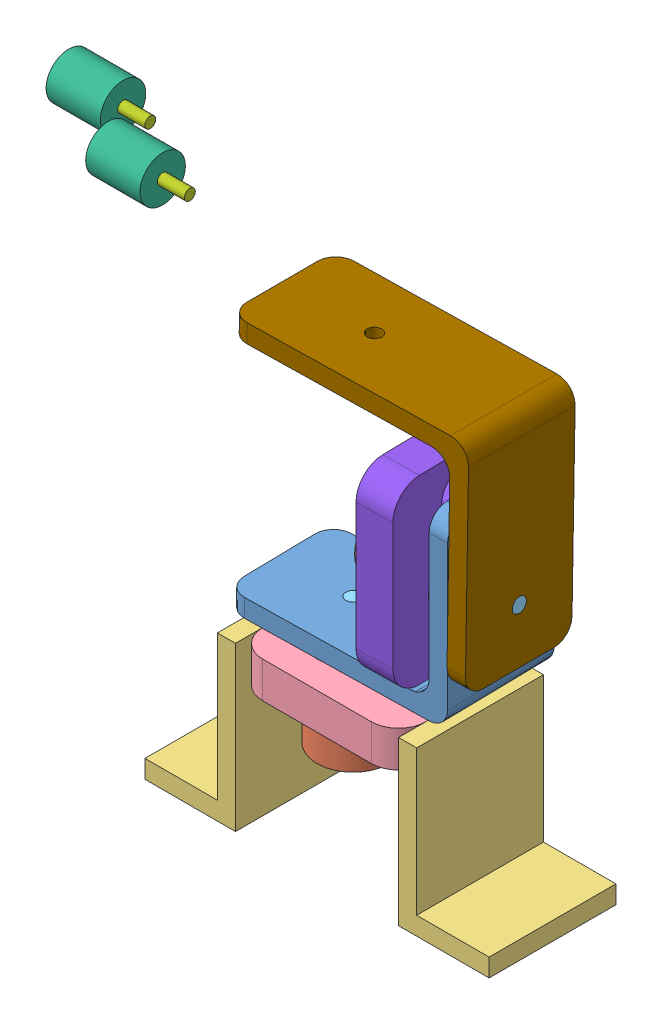
SolidWorks assembly Assemminubot, configuration Default. Lengths in mm.
Overall size (310.23 274.38 94.9).
14 component instances, 9 part files, 19 mates.
Components (placement in the parent):
- l link-1: l link [Default] at (-43.4938 20.615 74.495) x (0.999819 0 -0.019024) z (0.019024 0 0.999819) size (120 100 60)
- motor-1: motor [Default] at (67.057 70.615 102.397) x (-0.999819 0 0.019024) z (-0.014212 -0.664777 -0.746907) size (50 40 40)
- support-1: support [Default] at (-82.9303 -79.385 68.7286) size (50 90 70)
- motor-2: motor [Default] at (-2.9303 10.615 103.7286) x (0 -1 0) z (-0.977702 0 -0.209998) size (50 40 40)
- support-2: support [Default] at (107.0697 -79.385 138.7286) x (-1 0 0) z (0 0 -1) size (50 90 70)
- motorholder-2: motorholder [Default] at (12.0697 -9.385 103.7286) x (1 0 0) z (0 1 0) size (90 70 20)
- motorshaft-1: motorshaft [Default] at (-2.9303 30.615 103.7286) x (0 0 -1) z (0 -1 0) size (8 8 20)
- encoder-1: encoder [Default] at (-203.1636 158.0191 60.5643) size (30 25 25)
- encoder-2: encoder [Default] at (-133.2054 182.4977 108.6527) size (30 25 25)
- motorshaft-2: motorshaft [Default] at (87.0534 70.615 102.0165) x (0.007264 0.924225 0.38178) z (-0.999819 0 0.019024) size (8 8 20)
- encodershaft-2: encodershaft [Default] at (-103.2054 182.4977 108.6527) x (0 0 -1) z (1 0 0) size (6 6 15)
- encodershaft-3: encodershaft [Default] at (-158.1636 158.0191 60.5643) x (0 0 1) z (-1 0 0) size (6 6 15)
- motorholder1-1: motorholder1 [Default] at (37.0624 80.615 102.9677) x (0 1 0) z (0.999819 0 -0.019024) size (100 80 20)
- l link1-1: l link1 [Default] at (86.4926 40.1014 72.5445) x (-0.000329 0.999851 -0.017268) z (0.019021 0.017271 0.99967) size (120 130 60)
Mates (geometry in assembly coordinates):
- Coincident1: coincident anti-aligned: circle of motor-2; circle of motorshaft-1
- Coincident2: coincident anti-aligned: circle of motor-1; circle of motorshaft-2
- Coincident3: coincident anti-aligned: circle of encoder-1; circle of encodershaft-3
- Coincident6: coincident aligned: circle of encoder-2; circle of encodershaft-2
- Coincident8: coincident aligned: circle of l link-1; circle of motorshaft-2
- Concentric3: concentric anti-aligned: circle of motorshaft-1; circle of l link-1
- Coincident10: coincident aligned: plane of l link-1 through (-42.3524 30.615 134.4842) normal (0 1 0); plane of motorshaft-1 through (-2.9303 30.615 103.7286) normal (0 1 0)
- Coincident11: coincident anti-aligned: cylinder of motor-2 through (-2.9303 -39.385 103.7286) axis (0 1 0) radius 20; circle of motorholder-2
- Coincident15: coincident anti-aligned: line of support-1 through (-32.9303 10.615 138.7286) axis (0 0 -1); line of motorholder-2 through (-32.9303 10.615 83.7286) axis (0 0 1)
- Coincident17: coincident anti-aligned: line of support-2 through (57.0697 10.615 68.7286) axis (0 0 1); line of motorholder-2 through (57.0697 10.615 123.7286) axis (0 0 -1)
- Coincident18: coincident anti-aligned: plane of support-2 through (57.0697 -79.385 68.7286) normal (-1 0 0); plane of motorholder-2 through (57.0697 10.615 123.7286) normal (1 0 0)
- Coincident23: coincident anti-aligned: cylinder of motor-1 through (17.0661 70.615 103.3482) axis (0.999819 0 -0.019024) radius 20; circle of motorholder1-1
- Parallel4: parallel anti-aligned: plane of l link-1 through (-42.3524 30.615 134.4842) normal (0 1 0); plane of motorholder1-1 through (56.5832 30.615 77.5917) normal (0 -1 0)
- Coincident27: coincident anti-aligned: plane of support-1 through (-32.9303 -79.385 138.7286) normal (1 0 0); plane of motorholder-2 through (-32.9303 10.615 123.7286) normal (-1 0 0)
- Coincident28: coincident aligned: plane of motor-2 through (-2.9303 10.615 103.7286) normal (0 1 0); plane of motorholder-2 through (-17.9303 10.615 123.7286) normal (0 1 0)
- Coincident29: coincident aligned: line of l link-1 through (57.6295 30.615 132.5818) axis (-0.019024 0 -0.999819); line of motorholder1-1 through (57.5344 30.615 127.5827) axis (-0.019024 0 -0.999819)
- Coincident30: coincident aligned: circle of motorshaft-2; circle of l link1-1
- Coincident32: coincident aligned: plane of support-1 through (-82.9303 -79.385 138.7286) normal (0 0 1); plane of support-2 through (107.0697 -79.385 138.7286) normal (0 0 1)
- Width1: width anti-aligned: plane of motorholder-2 through (42.0697 10.615 68.7286) normal (0 0 -1); plane of motorholder-2 through (42.0697 10.615 138.7286) normal (0 0 1); plane of support-2 through (107.0697 -79.385 138.7286) normal (0 0 1); plane of support-1 through (-82.9303 -79.385 68.7286) normal (0 0 -1)
